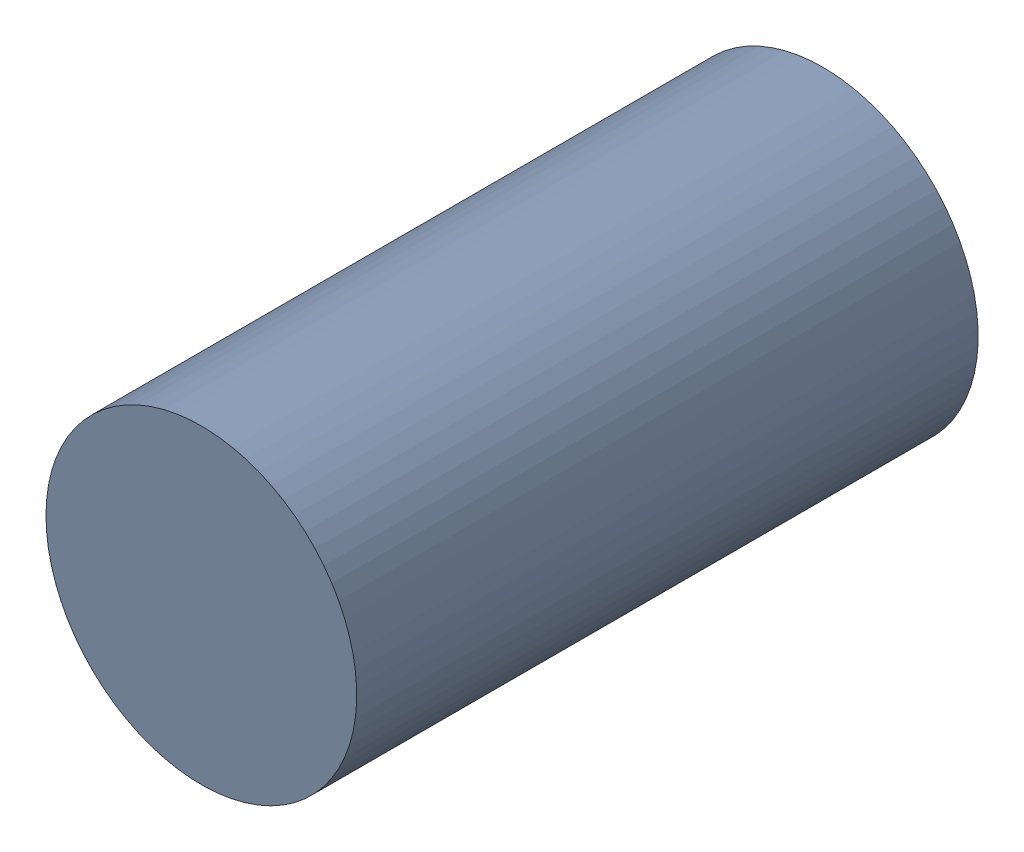
SolidWorks assembly MH9_2.step, configuration Default. Lengths in mm.
Overall size (1 1 2).
2 component instances, 1 part files, 0 mates.
Components (placement in the parent):
- 11929539264.step-1: 11929539264.step [Default] at (59.1753 107.3366 -1.5) x (-1 0 0) z (0 0 1) size (1 1 2)
  - Cylinder_2.step-7: Cylinder_2.step [Default] at origin size (1 1 2)
